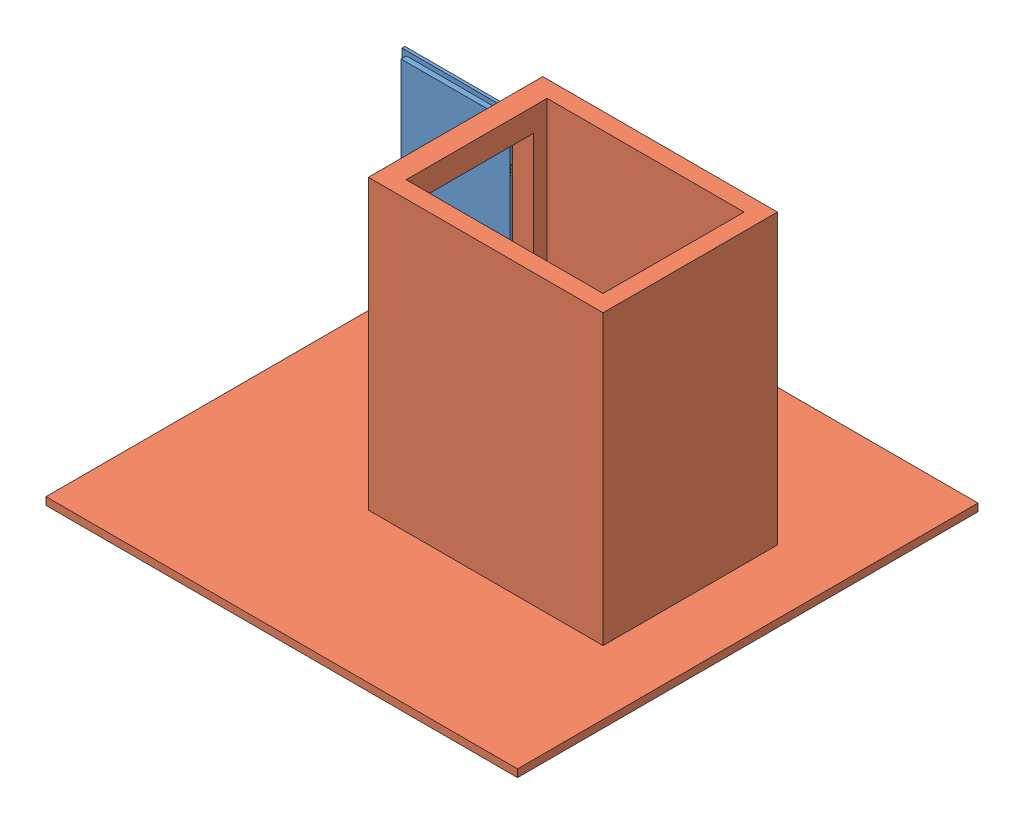
SolidWorks assembly Main Assembly, configuration Default. Lengths in mm.
Overall size (3107.91 1950 3035.14).
5 component instances, 5 part files, 21 mates.
Components (placement in the parent):
- gate-1: gate [Default] at (2413.5054 -1653.9699 1344.5335) x (0 0 1) z (-1 0 0) size (126.15 1755 747.47)
- wall-1: wall [Default] at (2423.5054 -1668.9987 1192.4312) size (3107.91 1950 3035.14)
- HingeP1-2: HingeP1 [Default] at (2418.5054 -237.962 1383.1389) x (0 1 0) z (1 0 0) size (60 40.34 12.83)
- HingeP2-2: HingeP2 [Default] at (2418.5054 -177.962 1383.1389) x (0 -1 0) z (-1 0 0) size (60 40.3 12.75)
- toilet seat-1: toilet seat [Default] at (3425.0541 -1678.9987 1792.5565) x (0 0 1) z (0 1 0) size (618.69 615.23 91.5)
Mates (geometry in assembly coordinates):
- Coincident6: coincident anti-aligned: plane of wall-1 through (4323.5054 -1673.9407 1392.4312) normal (0 0 1); plane of ? through (2423.5054 -290.2046 1392.4312) normal (0 0 -1)
- Parallel2: parallel anti-aligned: plane of wall-1 through (2423.5054 231.0013 1192.4312) normal (0 1 0); plane of ? through (2423.5054 -350.2046 1392.4312) normal (0 -1 0)
- Coincident7: coincident aligned: plane of wall-1 through (2423.5054 231.0013 1192.4312) normal (-1 0 0); plane of ? through (2423.5054 -290.2046 1392.4312) normal (-1 0 0)
- Concentric1: concentric anti-aligned: circle of ?; circle of ?
- Coincident11: coincident anti-aligned: plane of ? through (2419.581 -310.2046 1397.4312) normal (0 -1 0); plane of ? through (2419.581 -310.2046 1397.4312) normal (0 1 0)
- Lock2: lock: unknown of wall-1; unknown of ?
- Distance2: distance = 0 mm anti-aligned: plane of ?; plane of gate-1
- Coincident18: coincident aligned: plane of gate-1; plane of ?
- Coincident19: coincident: plane of gate-1 through (2397.4552 -1668.9987 1349.7716) normal (0 -1 0); plane of wall-1 through (2423.5054 -1668.9987 1192.4312) normal (0 -1 0)
- Parallel6: parallel anti-aligned: plane of wall-1 through (2423.5054 231.0013 1192.4312) normal (0 1 0); plane of HingeP1-2 through (2423.5054 -237.962 1383.1389) normal (0 -1 0)
- Coincident24: coincident anti-aligned: plane of wall-1 through (2423.5054 231.0013 1192.4312) normal (-1 0 0); plane of HingeP1-2 through (2423.5054 -237.962 1383.1389) normal (1 0 0)
- Parallel7: parallel aligned: plane of wall-1 through (2423.5054 231.0013 1192.4312) normal (-1 0 0); plane of HingeP1-2 through (2418.5054 -237.962 1383.1389) normal (-1 0 0)
- Lock5: lock: unknown of wall-1; unknown of HingeP1-2
- Concentric4: concentric aligned: circle of HingeP1-2; circle of HingeP2-2
- Coincident32: coincident anti-aligned: plane of HingeP1-2 through (2418.5054 -197.962 1387.0632) normal (0 -1 0); plane of HingeP2-2 through (2418.5054 -197.962 1387.0632) normal (0 1 0)
- Coincident34: coincident anti-aligned: plane of gate-1 through (2413.5054 71.0301 1344.5335) normal (1 0 0); plane of HingeP2-2 through (2413.5054 -177.962 1383.1389) normal (-1 0 0)
- Coincident37: coincident aligned: plane of gate-1 through (2413.5054 -1653.9699 1353.1389) normal (0 0 -1); plane of HingeP2-2 through (2413.5054 -177.962 1353.1389) normal (0 0 -1)
- LimitAngle1: limit planar angle = 0 rad anti-aligned: plane of HingeP1-2 through (2418.5054 -237.962 1383.1389) normal (-1 0 0); plane of HingeP2-2 through (2418.5054 -177.962 1383.1389) normal (1 0 0)
- Lock6: lock: unknown of gate-1; unknown of HingeP2-2
- Distance3: distance = 10 mm anti-aligned: plane of toilet seat-1 through (3308.9432 -1658.9987 1792.5565) normal (0 -1 0); plane of wall-1 through (2423.5054 -1668.9987 1192.4312) normal (0 1 0)
- Distance5: distance = 130 mm anti-aligned: plane of toilet seat-1 through (3616.5575 -1658.9987 2101.9023) normal (0 0 1); plane of wall-1 through (2562.1288 231.0013 2231.9023) normal (0 0 -1)
